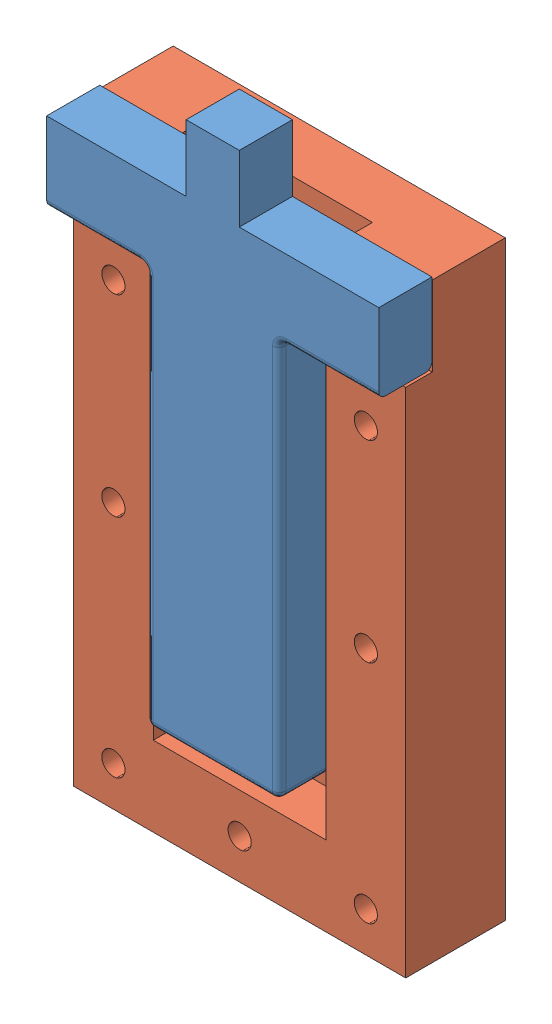
SolidWorks assembly gripper3, configuration ﾃﾞﾌｫﾙﾄ. Lengths in mm.
Overall size (50.05 99.37 19).
2 component instances, 2 part files, 1 mates.
Components (placement in the parent):
- gripper_inside3-1: gripper_inside3 [ﾃﾞﾌｫﾙﾄ] at (-11.9115 22.7896 78) size (50 82 8)
- gripper_outside3-1: gripper_outside3 [ﾃﾞﾌｫﾙﾄ] at (-11.857 28.424 82) x (1 0 0) z (0 -1 0) size (50 15 89)
Mates (geometry in assembly coordinates):
- 一致2: coincident anti-aligned: plane of gripper_inside3-1 through (-11.9115 22.7896 78) normal (0 0 -1); plane of gripper_outside3-1 through (13.143 28.424 78) normal (0 0 1)
